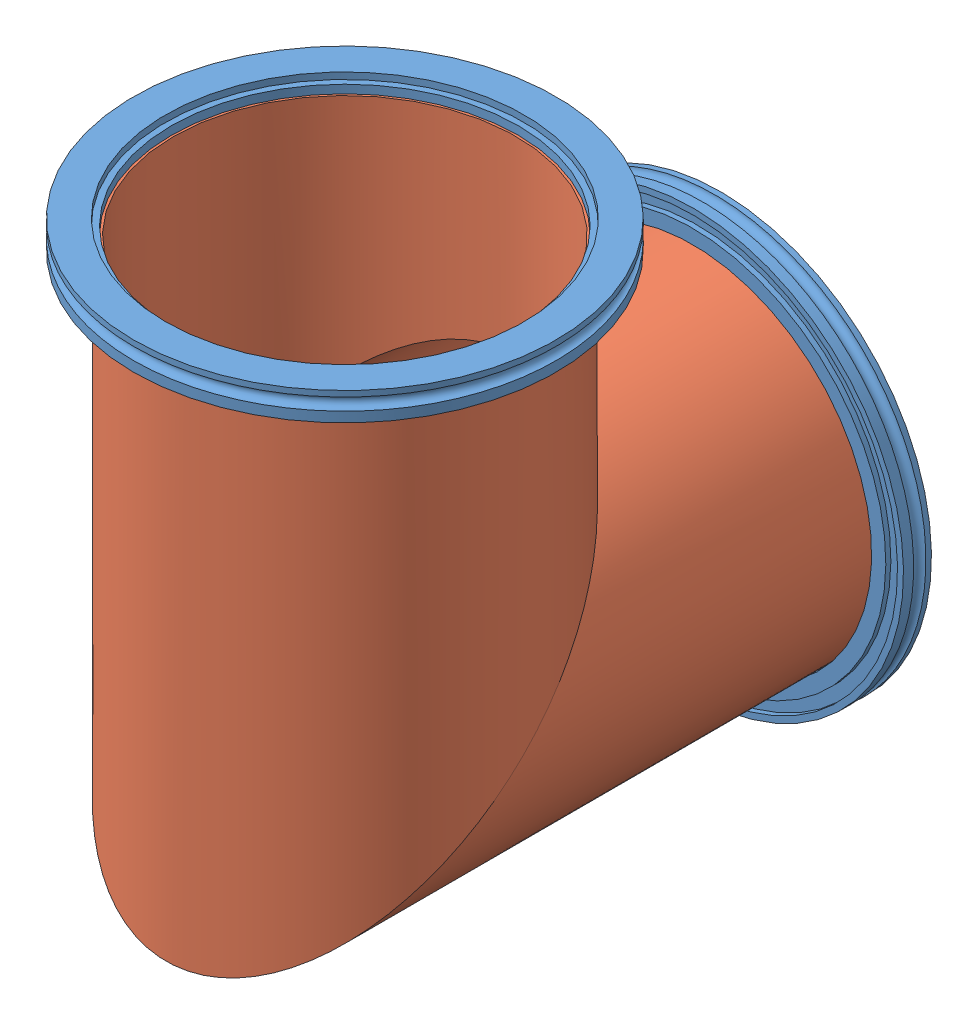
SolidWorks assembly 823002, configuration Default. Lengths in mm.
Overall size (252.98 286.76 250.32).
3 component instances, 2 part files, 5 mates.
Components (placement in the parent):
- 813002-1: 813002 [Default] at (62.2796 57.6202 169.5957) size (180.09 11.94 180.09)
- 813002-2: 813002 [Default] at (62.2796 -102.6538 9.3217) x (-0.620755 0.784005 0) z (-0.784005 -0.620755 0) size (180.09 11.94 180.09)
- 940308-1: 940308 [Default] at (62.2796 -26.4538 93.3957) x (0 0 -1) z (-1 0 0) size (230.12 230.12 152.4)
Mates (geometry in assembly coordinates):
- Coincident1: coincident anti-aligned: plane of 813002-1 through (138.7336 51.2702 169.5957) normal (0 -1 0); plane of 940308-1 through (62.2796 51.2702 169.5957) normal (0 1 0)
- Concentric1: concentric anti-aligned: cylinder of 813002-1 through (62.2796 57.6202 169.5957) axis (0 1 0) radius 76.454; cylinder of 940308-1 through (62.2796 51.2702 169.5957) axis (0 -1 0) radius 76.2
- Coincident2: coincident anti-aligned: plane of 813002-2 through (14.8205 -42.7135 15.6717) normal (0 0 1); plane of 940308-1 through (62.2796 -102.6538 15.6717) normal (0 0 -1)
- Concentric2: concentric anti-aligned: cylinder of 813002-2 through (62.2796 -102.6538 9.3217) axis (0 0 -1) radius 76.5048; cylinder of 940308-1 through (62.2796 -102.6538 15.6717) axis (0 0 1) radius 76.2
- Parallel1: parallel anti-aligned: plane of 940308-1 through (62.2796 -26.4538 93.3957) normal (-1 0 0)
